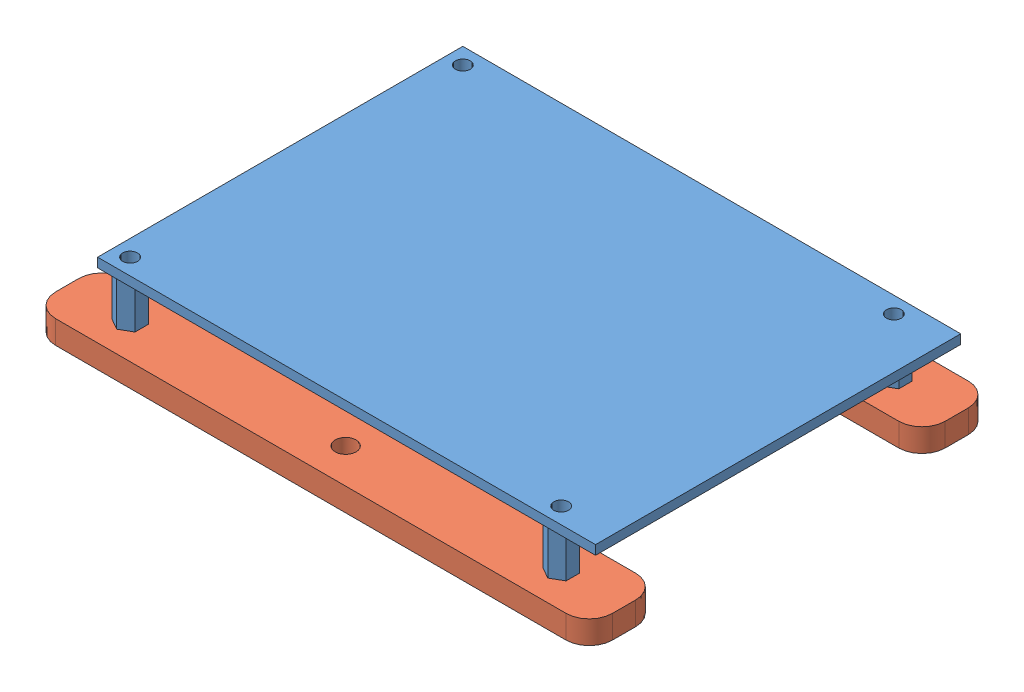
SolidWorks assembly Плата с креплением, configuration По умолчанию. Lengths in mm.
Overall size (120 30 86.7).
3 component instances, 2 part files, 9 mates.
Components (placement in the parent):
- Плата-1: Плата [По умолчанию] at origin size (107.3 25 78.7)
- Крепление-1: Крепление [По умолчанию] at (-10.05 -15 4) size (120 5 15)
- Крепление-2: Крепление [По умолчанию] at (-10.05 -15 -67.7) size (120 5 15)
Mates (geometry in assembly coordinates):
- Совпадение1: coincident aligned: plane of Плата-1 through (0 0 0) normal (0 0 1); plane of assembly through (0 0 0) normal (0 0 1)
- Совпадение2: coincident aligned: plane of Плата-1 through (0 0 0) normal (0 1 0); plane of assembly through (0 0 0) normal (0 1 0)
- Совпадение3: coincident aligned: plane of Плата-1 through (0 0 0) normal (1 0 0); plane of assembly through (0 0 0) normal (1 0 0)
- Концентричный1: concentric anti-aligned: cylinder of Плата-1 through (3.5 2 -3.5) axis (0 -1 0) radius 1.6; cylinder of Крепление-1 through (3.5 -15 -3.5) axis (0 1 0) radius 1.6
- Концентричный2: concentric anti-aligned: cylinder of Плата-1 through (96.4 2 -3.5) axis (0 -1 0) radius 1.6; cylinder of Крепление-1 through (96.4 -15 -3.5) axis (0 1 0) radius 1.6
- Совпадение4: coincident anti-aligned: plane of Плата-1 through (0 -10 0) normal (0 -1 0); plane of Крепление-1 through (-10.05 -10 4) normal (0 1 0)
- Концентричный3: concentric anti-aligned: cylinder of Плата-1 through (3.5 2 -75.2) axis (0 -1 0) radius 1.6; cylinder of Крепление-2 through (3.5 -15 -75.2) axis (0 1 0) radius 1.6
- Концентричный4: concentric anti-aligned: cylinder of Плата-1 through (96.4 2 -75.2) axis (0 -1 0) radius 1.6; cylinder of Крепление-2 through (96.4 -15 -75.2) axis (0 1 0) radius 1.6
- Совпадение5: coincident anti-aligned: plane of Плата-1 through (0 -10 0) normal (0 -1 0); plane of Крепление-2 through (-10.05 -10 -67.7) normal (0 1 0)
